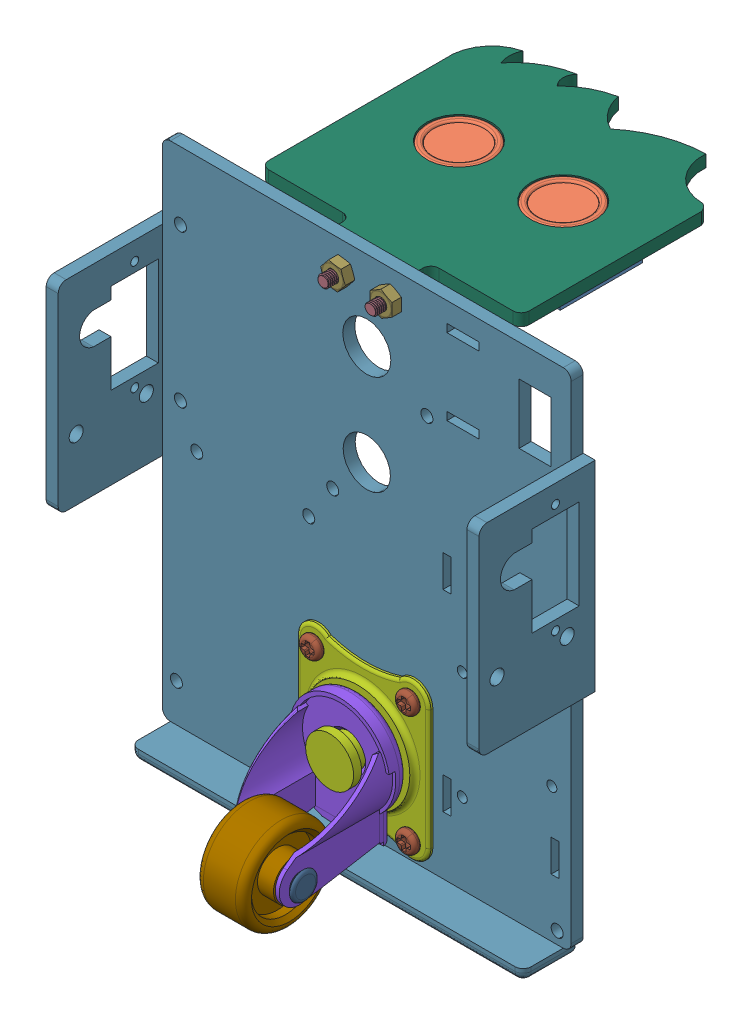
SolidWorks assembly DYOR_3D, configuration Predeterminado. Lengths in mm.
Overall size (108 131.39 103.03).
35 component instances, 15 part files, 12 mates.
Components (placement in the parent):
- HC-SR04 Ping Sensor-1: HC-SR04 Ping Sensor [Default] at (9.418 28.7888 -23.4611) x (0 0 -1) z (0 1 0) size (25.18 45 18.07)
  - PCB-1: PCB [Default] at origin size (20.5 45 1.75)
  - Transducer-1: Transducer [Default] at (0 -13 13.25) x (1 0 0) z (0 -1 0) size (15.88 12 15.88)
  - Transducer-2: Transducer [Default] at (0 13 13.25) x (1 0 0) z (0 -1 0) size (15.88 12 15.88)
  - 3 Pin Header 90 Degree-1: 3 Pin Header 90 Degree [Default] at (8.4275 0 -1.25) x (-1 0 0) z (0 -1 0) size (8 7.82 10)
  - 14 Pin SMT-1: 14 Pin SMT [Default] at (-0.35 -18.5 -0.85) x (0 -1 0) z (1 0 0) size (6 1.6 8.8)
  - 14 Pin SMT-2: 14 Pin SMT [Default] at (0 -0.3826 -0.85) x (1 0 0) z (0 1 0) size (6 1.6 8.8)
  - 14 Pin SMT-3: 14 Pin SMT [Default] at (0 17.5274 -0.85) x (1 0 0) z (0 1 0) size (6 1.6 8.8)
  - Cap1 SMT-1: Cap1 SMT [Default] at (-1.755 7.4774 -0.9689) x (0 1 0) z (-1 0 0) size (4.5 1.84 1.75)
  - Cap1 SMT-2: Cap1 SMT [Default] at (6.835 7.4774 -0.9689) x (0 1 0) z (-1 0 0) size (4.5 1.84 1.75)
  - Cap1 SMT-3: Cap1 SMT [Default] at (-6.835 7.4774 -0.9689) x (0 1 0) z (-1 0 0) size (4.5 1.84 1.75)
  - Cap1 SMT-4: Cap1 SMT [Default] at (4.295 7.4774 -0.9689) x (0 1 0) z (-1 0 0) size (4.5 1.84 1.75)
  - Cap1 SMT-5: Cap1 SMT [Default] at (1.755 7.4774 -0.9689) x (0 1 0) z (-1 0 0) size (4.5 1.84 1.75)
  - Cap1 SMT-6: Cap1 SMT [Default] at (-4.295 7.4774 -0.9689) x (0 1 0) z (-1 0 0) size (4.5 1.84 1.75)
  - HC-SR04 Crystal-1: HC-SR04 Crystal [Default] at (-8.3 0 1.75) x (0 -1 0) z (0 0 1) size (10 3.5 2.7)
- CA-1: CA [Predeterminado] at (-2.207 18.0036 0) size (33 45.94 43.2)
  - Caster Wheel-1: Caster Wheel [Default] at (57.6387 -78.841 57.7572) x (0 1 0) z (-1 0 0) size (45.94 37.59 33)
    - caster holder-1: caster holder [Default] at (-24.0751 44.7184 29.5137) x (1 0 0) z (0 0 -1) size (39 9.27 33)
    - holder-1: holder [Default] at (-1.5751 42.9484 46.0137) x (0 0 1) z (1 0 0) size (25 28.07 31.31)
    - caster wheel-1: caster wheel [Default] at (-15.6961 19.9484 46.0137) x (0.997275 0.073773 0) z (0 0 1) size (23 23 14)
    - Part4-1: Part4 [Default] at (-15.6961 19.9484 55.0137) x (-0.978448 0.206495 0) z (0 0 -1) size (7 7 20)
  - M3x6 Philips Screw-1: M3x6 Philips Screw [Predeterminado] at (23.625 -65.4161 13.5389) size (5.3 5.3 7.81)
  - M3x6 Philips Screw-2: M3x6 Philips Screw [Predeterminado] at (-0.375 -65.4161 13.5389) size (5.3 5.3 7.81)
  - M3x6 Philips Screw-3: M3x6 Philips Screw [Predeterminado] at (-0.375 -95.4161 13.5389) size (5.3 5.3 7.81)
  - M3x6 Philips Screw-4: M3x6 Philips Screw [Predeterminado] at (23.625 -95.4161 13.5389) size (5.3 5.3 7.81)
  - M3 Nut-1: M3 Nut [Predeterminado] at (23.625 -65.4161 11.0389) size (6.27 6.27 2.71)
  - M3 Nut-2: M3 Nut [Predeterminado] at (-0.375 -65.4161 11.0389) size (6.27 6.27 2.71)
  - M3 Nut-3: M3 Nut [Predeterminado] at (-0.375 -95.4161 11.0389) size (6.27 6.27 2.71)
  - M3 Nut-4: M3 Nut [Predeterminado] at (23.625 -95.4161 11.0389) size (6.27 6.27 2.71)
- M3x10 Philips Screw-2: M3x10 Philips Screw [Predeterminado] at (3.418 36.0388 7.5389) x (-0.665771 0.746156 0) z (0 0 -1) size (5.3 5.3 11.8)
- M3x10 Philips Screw-3: M3x10 Philips Screw [Predeterminado] at (15.418 36.0388 7.5389) x (0.006663 -0.999978 0) z (0 0 -1) size (5.3 5.3 11.8)
- M3 Nut-1: M3 Nut [Predeterminado] at (3.418 36.0388 16.5389) x (0.934299 0.356491 0) z (0 0 1) size (6.27 6.27 2.71)
- M3 Nut-2: M3 Nut [Predeterminado] at (15.418 36.0388 11.0389) x (-0.487763 -0.872976 0) z (0 0 -1) size (6.27 6.27 2.71)
- Base-1: Base [Predeterminado] at (60.418 -80.9125 12.5389) size (108 128.45 29)
- Front-2: Front [Predeterminado] at (30.3569 39.5388 1.4932) x (1 0 0) z (0 1 0) size (65 62.44 11)
Mates (geometry in assembly coordinates):
- Concéntrica15: concentric: circle of CA-1/Caster Wheel-1/caster holder-1; circle of Base-1
- Coincidente14: coincident: plane of CA-1/M3 Nut-4 through (21.418 -77.4125 9.5389) normal (0 0 1); plane of Base-1 through (-39.582 40.5388 9.5389) normal (0 0 -1)
- Concéntrica16: concentric: circle of CA-1/M3 Nut-1; circle of Base-1
- Coincidente23: coincident: plane of Base-1 through (-39.582 40.5388 9.5389) normal (0 0 -1); plane of Front-2 through (-0.582 42.5388 9.5389) normal (0 0 1)
- Paralelo2: parallel: plane of Base-1 through (-39.582 42.5388 9.5389) normal (0 1 0); plane of Front-2 through (-2.582 42.5388 8.5374) normal (0 1 0)
- Coincidente28: coincident: plane of M3x10 Philips Screw-3 through (13.8181 36.0281 7.5389) normal (0 0 1); plane of Front-2 through (15.418 36.0388 7.5389) normal (0 0 -1)
- Concéntrica22: concentric: circle of M3x10 Philips Screw-2; circle of Base-1
- Coincidente30: coincident: plane of M3x10 Philips Screw-2 through (4.6119 37.104 7.5389) normal (0 0 1); plane of Front-2 through (3.418 36.0388 7.5389) normal (0 0 -1)
- Concéntrica23: concentric: circle of M3 Nut-1; circle of Base-1
- Concéntrica24: concentric: circle of M3 Nut-2; circle of Base-1
- Coincidente31: coincident: plane of M3 Nut-1 through (3.418 36.0388 12.5389) normal (0 0 -1); plane of Base-1 through (-39.582 40.5388 12.5389) normal (0 0 1)
- Coincidente32: coincident: plane of M3 Nut-2 through (15.418 36.0388 12.5389) normal (0 0 -1); plane of Base-1 through (-39.582 40.5388 12.5389) normal (0 0 1)
